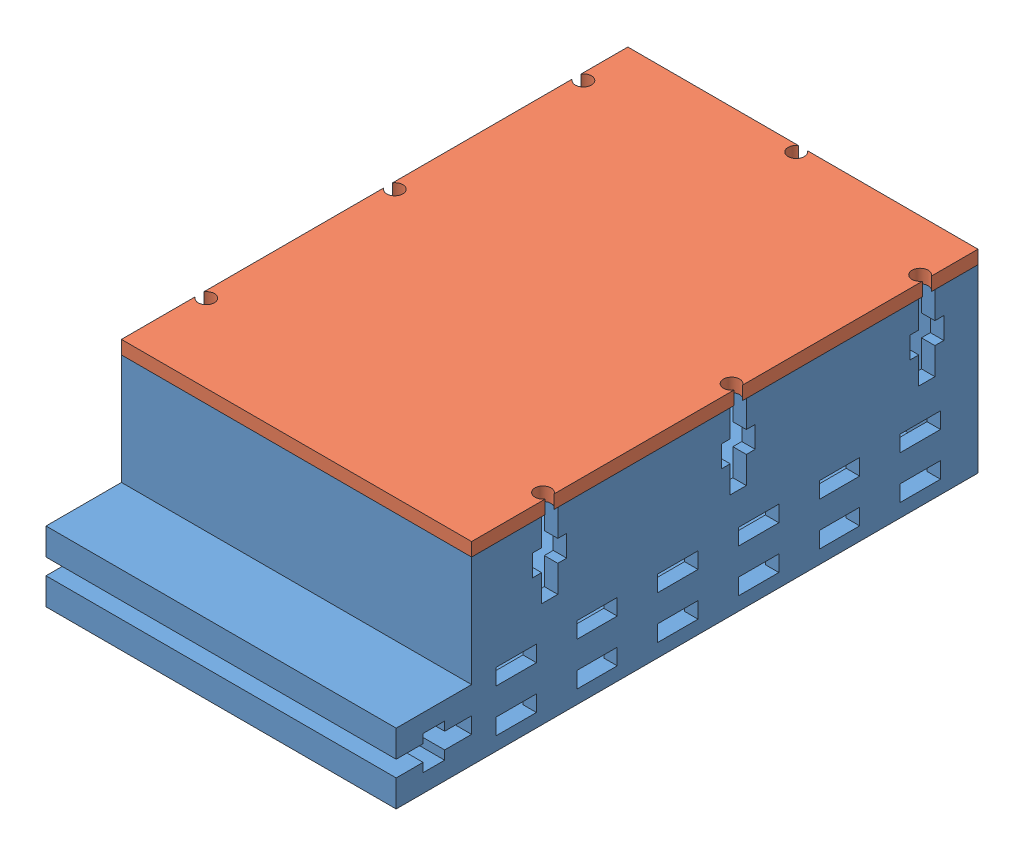
SolidWorks assembly breadboard, configuration Default. Lengths in mm.
Overall size (65 36 108).
2 component instances, 2 part files, 3 mates.
Components (placement in the parent):
- breadboard_box-1: breadboard_box [Default] at (15.7104 65.8808 89.4139) size (65 33.5 108)
- breadboard_cover-1: breadboard_cover [Default] at (15.7104 101.8808 89.4139) x (-1 0 0) z (0 -1 0) size (65 94 2.5)
Mates (geometry in assembly coordinates):
- Coincident5: coincident aligned: plane of breadboard_box-1 through (-16.7896 99.3808 136.4139) normal (0 0 1); plane of breadboard_cover-1 through (48.2104 99.3808 136.4139) normal (0 0 1)
- Coincident6: coincident aligned: plane of breadboard_box-1 through (-16.7896 99.3808 42.4139) normal (-1 0 0); plane of breadboard_cover-1 through (-16.7896 99.3808 42.4139) normal (-1 0 0)
- Coincident7: coincident anti-aligned: plane of breadboard_box-1 through (15.7104 99.3808 89.4139) normal (0 1 0); plane of breadboard_cover-1 through (15.7104 99.3808 89.4139) normal (0 -1 0)
